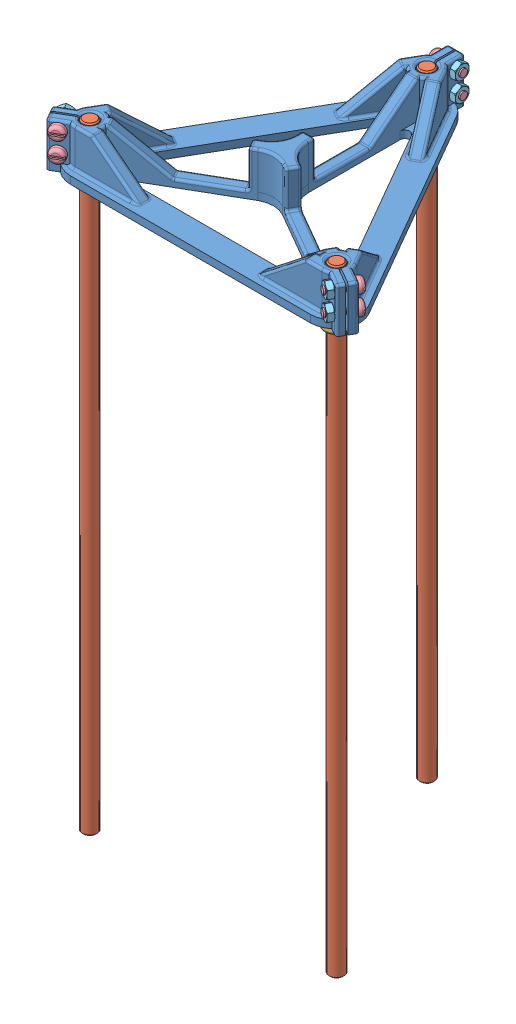
SolidWorks assembly Calibration Rod Assembly, configuration Default. Lengths in mm.
Overall size (125.66 250.1 109.85).
19 component instances, 5 part files, 36 mates.
Components (placement in the parent):
- End-Effector Calibration Block-1: End-Effector Calibration Block [Default] at (52.3583 54.6592 97.7326) size (123.55 18.1 107.8)
- Calibration Rod-1: Calibration Rod [Default] at (2.3583 -177.3408 126.6001) size (6 250 6)
- Calibration Rod-2: Calibration Rod [Default] at (52.3583 -177.3408 39.9976) x (0.982082 0 -0.188455) z (0.188455 0 0.982082) size (6 250 6)
- Calibration Rod-3: Calibration Rod [Default] at (102.3583 -177.3408 126.6001) x (0.918365 0 -0.395734) z (0.395734 0 0.918365) size (6 250 6)
- Calibration Rod Sleeve-1: Calibration Rod Sleeve [Default] at (2.3583 54.6592 126.6001) x (-0.837169 0 -0.546944) z (-0.546944 0 0.837169) size (9.8 5 9.8)
- Calibration Rod Sleeve-2: Calibration Rod Sleeve [Default] at (102.3583 54.6592 126.6001) x (-0.925243 0 -0.379375) z (-0.379375 0 0.925243) size (9.8 5 9.8)
- Calibration Rod Sleeve-3: Calibration Rod Sleeve [Default] at (52.3583 54.6592 39.9976) x (-0.985271 0 -0.170998) z (-0.170998 0 0.985271) size (9.8 5 9.8)
- pan slot head_am-1: pan slot head_am [B18.6.7M - M3 x 0.5 x 10 Slotted PHMS --10N] at (112.6147 69.1592 125.7089) x (-0.5 0 0.866025) z (-0.866025 0 -0.5) size (12.4 5.6 5.6)
- pan slot head_am-2: pan slot head_am [B18.6.7M - M3 x 0.5 x 10 Slotted PHMS --10N] at (112.6147 61.1592 125.7089) x (-0.5 0 0.866025) z (-0.866025 0 -0.5) size (12.4 5.6 5.6)
- pan slot head_am-3: pan slot head_am [B18.6.7M - M3 x 0.5 x 10 Slotted PHMS --10N] at (46.4583 69.1592 31.5609) size (12.4 5.6 5.6)
- pan slot head_am-4: pan slot head_am [B18.6.7M - M3 x 0.5 x 10 Slotted PHMS --10N] at (46.4583 61.1592 31.5609) size (12.4 5.6 5.6)
- pan slot head_am-6: pan slot head_am [B18.6.7M - M3 x 0.5 x 10 Slotted PHMS --10N] at (-1.9981 69.1592 135.928) x (-0.5 0 -0.866025) z (0.866025 0 -0.5) size (12.4 5.6 5.6)
- pan slot head_am-7: pan slot head_am [B18.6.7M - M3 x 0.5 x 10 Slotted PHMS --10N] at (-1.9981 61.1592 135.928) x (-0.5 0 -0.866025) z (0.866025 0 -0.5) size (12.4 5.6 5.6)
- hex nut style 1_am-1: hex nut style 1_am [B18.2.4.1M - Hex nut, Style 1,  M3 x 0.5 --D-N] at (-7.8981 69.1592 125.7089) x (-0.866025 0 0.5) z (-0.5 0 -0.866025) size (5.5 6.35 2.4)
- hex nut style 1_am-2: hex nut style 1_am [B18.2.4.1M - Hex nut, Style 1,  M3 x 0.5 --D-N] at (-7.8981 61.1592 125.7089) x (-0.866025 0 0.5) z (-0.5 0 -0.866025) size (5.5 6.35 2.4)
- hex nut style 1_am-3: hex nut style 1_am [B18.2.4.1M - Hex nut, Style 1,  M3 x 0.5 --D-N] at (58.2583 69.1592 31.5609) x (0 0 -1) z (1 0 0) size (5.5 6.35 2.4)
- hex nut style 1_am-4: hex nut style 1_am [B18.2.4.1M - Hex nut, Style 1,  M3 x 0.5 --D-N] at (58.2583 61.1592 31.5609) x (0 0 -1) z (1 0 0) size (5.5 6.35 2.4)
- hex nut style 1_am-5: hex nut style 1_am [B18.2.4.1M - Hex nut, Style 1,  M3 x 0.5 --D-N] at (106.7147 69.1592 135.928) x (0.866025 0 0.5) z (-0.5 0 0.866025) size (5.5 6.35 2.4)
- hex nut style 1_am-6: hex nut style 1_am [B18.2.4.1M - Hex nut, Style 1,  M3 x 0.5 --D-N] at (106.7147 61.1592 135.928) x (0.866025 0 0.5) z (-0.5 0 0.866025) size (5.5 6.35 2.4)
Mates (geometry in assembly coordinates):
- Concentric2: concentric aligned: cylinder of End-Effector Calibration Block-1 through (2.3583 57.6592 126.6001) axis (0 -1 0) radius 3.1; cylinder of Calibration Rod-1 through (2.3583 72.6592 126.6001) axis (0 -1 0) radius 3
- Coincident1: coincident aligned: plane of End-Effector Calibration Block-1 through (2.3583 72.6592 126.6001) normal (0 1 0); plane of Calibration Rod-1 through (2.3583 72.6592 126.6001) normal (0 1 0)
- Coincident2: coincident aligned: plane of End-Effector Calibration Block-1 through (2.3583 72.6592 126.6001) normal (0 1 0); plane of Calibration Rod-2 through (52.3583 72.6592 39.9976) normal (0 1 0)
- Concentric3: concentric aligned: cylinder of End-Effector Calibration Block-1 through (52.3583 57.6592 39.9976) axis (0 -1 0) radius 3.1; cylinder of Calibration Rod-2 through (52.3583 72.6592 39.9976) axis (0 -1 0) radius 3
- Coincident3: coincident aligned: plane of End-Effector Calibration Block-1 through (2.3583 72.6592 126.6001) normal (0 1 0); plane of Calibration Rod-3 through (102.3583 72.6592 126.6001) normal (0 1 0)
- Concentric4: concentric aligned: cylinder of End-Effector Calibration Block-1 through (102.3583 57.6592 126.6001) axis (0 -1 0) radius 3.1; cylinder of Calibration Rod-3 through (102.3583 72.6592 126.6001) axis (0 -1 0) radius 3
- Concentric5: concentric anti-aligned: cylinder of Calibration Rod-1 through (2.3583 72.6592 126.6001) axis (0 -1 0) radius 3; cylinder of Calibration Rod Sleeve-1 through (2.3583 49.6592 126.6001) axis (0 1 0) radius 3.125
- Coincident5: coincident anti-aligned: plane of End-Effector Calibration Block-1 through (52.3583 54.6592 97.7326) normal (0 -1 0); plane of Calibration Rod Sleeve-1 through (2.3583 54.6592 126.6001) normal (0 1 0)
- Coincident6: coincident anti-aligned: plane of End-Effector Calibration Block-1 through (52.3583 54.6592 97.7326) normal (0 -1 0); plane of Calibration Rod Sleeve-2 through (102.3583 54.6592 126.6001) normal (0 1 0)
- Concentric6: concentric anti-aligned: cylinder of Calibration Rod-3 through (102.3583 72.6592 126.6001) axis (0 -1 0) radius 3; cylinder of Calibration Rod Sleeve-2 through (102.3583 49.6592 126.6001) axis (0 1 0) radius 3.125
- Coincident7: coincident anti-aligned: plane of End-Effector Calibration Block-1 through (52.3583 54.6592 97.7326) normal (0 -1 0); plane of Calibration Rod Sleeve-3 through (52.3583 54.6592 39.9976) normal (0 1 0)
- Concentric7: concentric anti-aligned: cylinder of Calibration Rod-2 through (52.3583 72.6592 39.9976) axis (0 -1 0) radius 3; cylinder of Calibration Rod Sleeve-3 through (52.3583 49.6592 39.9976) axis (0 1 0) radius 3.125
- Concentric8: concentric aligned: cylinder of End-Effector Calibration Block-1 through (77.7369 69.1592 186.119) axis (0.5 0 -0.866025) radius 1.6; cylinder of pan slot head_am-1 through (125.3147 69.1592 103.7119) axis (0.5 0 -0.866025) radius 2.8
- Coincident8: coincident anti-aligned: plane of End-Effector Calibration Block-1 through (114.5006 87.5673 129.569) normal (0.5 0 -0.866025); plane of pan slot head_am-1 through (111.4147 70.6592 127.7874) normal (-0.5 0 0.866025)
- Concentric9: concentric aligned: cylinder of End-Effector Calibration Block-1 through (77.7369 61.1592 186.119) axis (0.5 0 -0.866025) radius 1.6; cylinder of pan slot head_am-2 through (125.3147 61.1592 103.7119) axis (0.5 0 -0.866025) radius 2.8
- Coincident9: coincident anti-aligned: plane of End-Effector Calibration Block-1 through (114.5006 87.5673 129.569) normal (0.5 0 -0.866025); plane of pan slot head_am-2 through (111.4147 62.6592 127.7874) normal (-0.5 0 0.866025)
- Concentric10: concentric aligned: cylinder of End-Effector Calibration Block-1 through (110.9727 69.1592 31.5609) axis (-1 0 0) radius 1.6; cylinder of pan slot head_am-3 through (21.0583 69.1592 31.5609) axis (-1 0 0) radius 2.8
- Coincident10: coincident anti-aligned: plane of End-Effector Calibration Block-1 through (48.8583 83.6161 27.9976) normal (-1 0 0); plane of pan slot head_am-3 through (48.8583 70.6592 31.5609) normal (1 0 0)
- Concentric11: concentric aligned: cylinder of End-Effector Calibration Block-1 through (110.9727 61.1592 31.5609) axis (-1 0 0) radius 1.6; cylinder of pan slot head_am-4 through (21.0583 61.1592 31.5609) axis (-1 0 0) radius 2.8
- Coincident11: coincident anti-aligned: plane of End-Effector Calibration Block-1 through (48.8583 83.6161 27.9976) normal (-1 0 0); plane of pan slot head_am-4 through (48.8583 62.6592 31.5609) normal (1 0 0)
- Concentric13: concentric aligned: cylinder of End-Effector Calibration Block-1 through (-50.5883 69.1592 51.7673) axis (0.5 0 0.866025) radius 1.6; cylinder of pan slot head_am-6 through (10.7019 69.1592 157.9251) axis (0.5 0 0.866025) radius 2.8
- Coincident12: coincident anti-aligned: plane of End-Effector Calibration Block-1 through (-6.284 87.5673 135.6312) normal (0.5 0 0.866025); plane of pan slot head_am-6 through (-3.1981 70.6592 133.8496) normal (-0.5 0 -0.866025)
- Concentric14: concentric aligned: cylinder of End-Effector Calibration Block-1 through (-50.5883 61.1592 51.7673) axis (0.5 0 0.866025) radius 1.6; cylinder of pan slot head_am-7 through (10.7019 61.1592 157.9251) axis (0.5 0 0.866025) radius 2.8
- Coincident13: coincident anti-aligned: plane of End-Effector Calibration Block-1 through (-6.284 87.5673 135.6312) normal (0.5 0 0.866025); plane of pan slot head_am-7 through (-3.1981 62.6592 133.8496) normal (-0.5 0 -0.866025)
- Concentric15: concentric anti-aligned: cylinder of End-Effector Calibration Block-1 through (-50.5883 69.1592 51.7673) axis (0.5 0 0.866025) radius 1.6; cylinder of hex nut style 1_am-1 through (4.6207 69.1592 147.392) axis (-0.5 0 -0.866025) radius 1.5
- Coincident14: coincident anti-aligned: plane of End-Effector Calibration Block-1 through (-9.784 87.5673 129.569) normal (-0.5 0 -0.866025); plane of hex nut style 1_am-1 through (-6.6981 72.3346 127.7874) normal (0.5 0 0.866025)
- Concentric16: concentric anti-aligned: cylinder of End-Effector Calibration Block-1 through (-50.5883 61.1592 51.7673) axis (0.5 0 0.866025) radius 1.6; cylinder of hex nut style 1_am-2 through (4.6207 61.1592 147.392) axis (-0.5 0 -0.866025) radius 1.5
- Coincident15: coincident anti-aligned: plane of End-Effector Calibration Block-1 through (-9.784 87.5673 129.569) normal (-0.5 0 -0.866025); plane of hex nut style 1_am-2 through (-6.6981 64.3346 127.7874) normal (0.5 0 0.866025)
- Concentric17: concentric anti-aligned: cylinder of End-Effector Calibration Block-1 through (110.9727 69.1592 31.5609) axis (-1 0 0) radius 1.6; cylinder of hex nut style 1_am-3 through (33.2208 69.1592 31.5609) axis (1 0 0) radius 1.5
- Coincident16: coincident anti-aligned: plane of End-Effector Calibration Block-1 through (55.8583 83.6161 27.9976) normal (1 0 0); plane of hex nut style 1_am-3 through (55.8583 72.3346 31.5609) normal (-1 0 0)
- Concentric18: concentric anti-aligned: cylinder of End-Effector Calibration Block-1 through (110.9727 61.1592 31.5609) axis (-1 0 0) radius 1.6; cylinder of hex nut style 1_am-4 through (33.2208 61.1592 31.5609) axis (1 0 0) radius 1.5
- Coincident17: coincident anti-aligned: plane of End-Effector Calibration Block-1 through (55.8583 83.6161 27.9976) normal (1 0 0); plane of hex nut style 1_am-4 through (55.8583 64.3346 31.5609) normal (-1 0 0)
- Concentric19: concentric anti-aligned: cylinder of End-Effector Calibration Block-1 through (77.7369 69.1592 186.119) axis (0.5 0 -0.866025) radius 1.6; cylinder of hex nut style 1_am-5 through (119.2335 69.1592 114.2449) axis (-0.5 0 0.866025) radius 1.5
- Coincident18: coincident anti-aligned: plane of End-Effector Calibration Block-1 through (111.0006 87.5673 135.6312) normal (-0.5 0 0.866025); plane of hex nut style 1_am-5 through (107.9147 72.3346 133.8496) normal (0.5 0 -0.866025)
- Concentric20: concentric anti-aligned: cylinder of End-Effector Calibration Block-1 through (77.7369 61.1592 186.119) axis (0.5 0 -0.866025) radius 1.6; cylinder of hex nut style 1_am-6 through (119.2335 61.1592 114.2449) axis (-0.5 0 0.866025) radius 1.5
- Coincident19: coincident anti-aligned: plane of End-Effector Calibration Block-1 through (111.0006 87.5673 135.6312) normal (-0.5 0 0.866025); plane of hex nut style 1_am-6 through (107.9147 64.3346 133.8496) normal (0.5 0 -0.866025)
